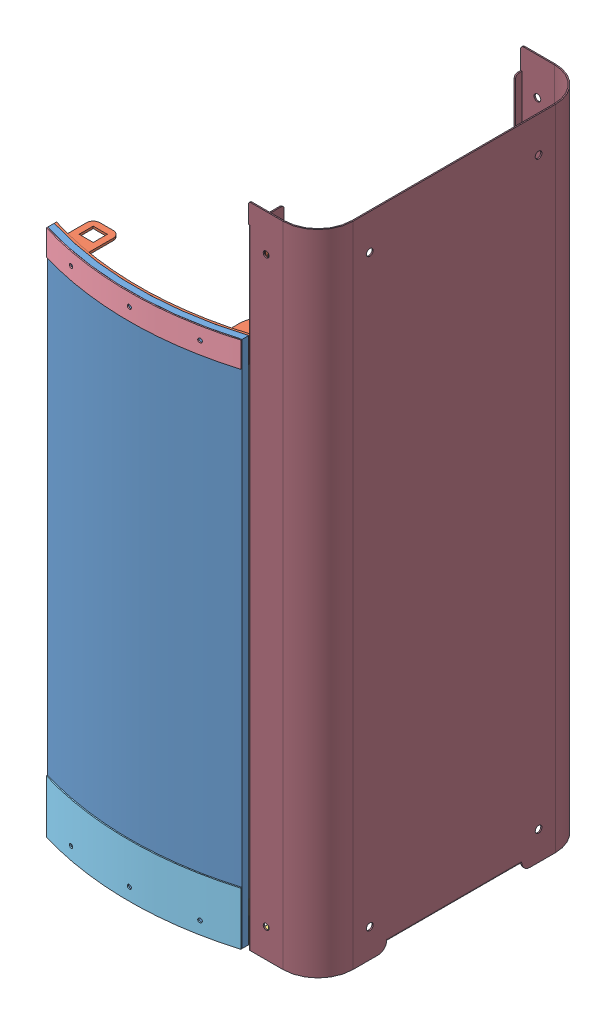
SolidWorks assembly PBS_600_DOOR, configuration Default. Lengths in mm.
Overall size (201.73 488.1 218.37).
13 component instances, 13 part files, 25 mates.
Components (placement in the parent):
- PBS_601_P_DOOR_PANEL-1: PBS_601_P_DOOR_PANEL [Default] at (0.536 -205.1011 -3.8342) size (146.34 397 15.77)
- PBS_610_S_DOOR_HINGE BRKT_T-1: PBS_610_S_DOOR_HINGE BRKT_T [Default] at (86.406 35.5639 -9.1792) x (-1 0 0) z (0 0 -1) size (165.39 19.05 41.9)
- PBS_611_S_DOOR_HINGE BRKT_B-2: PBS_611_S_DOOR_HINGE BRKT_B [Default] at (86.406 35.5639 -9.1792) x (-1 0 0) z (0 0 -1) size (165.39 19.05 41.9)
- PBS_620_S_DOOR_HINGE VALENCE_T-1: PBS_620_S_DOOR_HINGE VALENCE_T [Default] at (0.536 -205.1011 -3.8342) size (146.34 19.05 11.68)
- PBS_621_S_DOOR_HINGE VALENCE_B-1: PBS_621_S_DOOR_HINGE VALENCE_B [Default] at (0.536 -205.1011 -3.8342) size (146.34 39.88 11.68)
- PBS_605_M_DOOR_AXLE-1: PBS_605_M_DOOR_AXLE [Default] at (86.406 31.3179 -9.1792) size (8.29 473.71 9.13)
- PBS_652_X_DOOR_HINGE GEAR-1: PBS_652_X_DOOR_HINGE GEAR [Default] at (86.406 35.5639 -9.1792) size (16 6.35 16)
- PBS_650_X_DOOR_DAMPER_b-1: PBS_650_X_DOOR_DAMPER_b [Default] at (94.9554 191.421 -15.4222) x (1 0 0) z (0 1 0) size (15 24 6.6)
- PBS_631_S_DOOR_BRKT_SWITCH-1: PBS_631_S_DOOR_BRKT_SWITCH [Default] at (-74.2345 -196.269 -0.9914) size (25.53 57.15 15.88)
- PBS_654_X_DOOR_SWITCH-1: PBS_654_X_DOOR_SWITCH [Default] at (109.5595 154.0375 -21.0385) x (1 0 0) z (0 -1 0) size (28.57 6.35 44.56)
- PBS_630_S_DOOR_BRKT_DAMPER-2: PBS_630_S_DOOR_BRKT_DAMPER [Default] at (-75.646 -196.269 0.3458) size (47.5 58.8 31.61)
- PBS_640_X_DOOR_SPRING-TORQUED-1: PBS_640_X_DOOR_SPRING-TORQUED [Default] at (86.406 181.129 -9.1792) x (-0.853041 0 0.521844) z (0 -1 0) size (13.63 19.93 20.71)
- PBS_210_S_SHELL_R_b-2: PBS_210_S_SHELL_R_b [Default] at (-74.995 -196.2231 -1.3052) size (52.58 487.68 204.98)
Mates (geometry in assembly coordinates):
- Concentric1: concentric anti-aligned: cylinder of PBS_601_P_DOOR_PANEL-1 through (0.536 193.1709 -241.4064) axis (0 -1 0) radius 253.492; cylinder of PBS_610_S_DOOR_HINGE BRKT_T-1 through (0.536 174.1209 -241.4064) axis (0 1 0) radius 247.0785
- Concentric2: concentric aligned: cylinder of PBS_601_P_DOOR_PANEL-1 through (41.0204 182.3759 -33.1324) axis (0.190809 0 0.981627) radius 2.159; cylinder of PBS_610_S_DOOR_HINGE BRKT_T-1 through (41.0204 182.3759 -33.1324) axis (0.190809 0 0.981627) radius 1.524
- Concentric8: concentric anti-aligned: cylinder of PBS_601_P_DOOR_PANEL-1 through (0.536 193.1709 -241.4064) axis (0 -1 0) radius 253.492; cylinder of PBS_620_S_DOOR_HINGE VALENCE_T-1 through (0.536 174.1209 -241.4064) axis (0 1 0) radius 253.492
- Concentric9: concentric aligned: cylinder of PBS_601_P_DOOR_PANEL-1 through (41.0204 182.3759 -33.1324) axis (0.190809 0 0.981627) radius 2.159; cylinder of PBS_620_S_DOOR_HINGE VALENCE_T-1 through (41.0204 182.3759 -33.1324) axis (0.190809 0 0.981627) radius 1.524
- Concentric10: concentric aligned: cylinder of PBS_601_P_DOOR_PANEL-1 through (0.536 193.1709 -241.4064) axis (0 -1 0) radius 253.492; cylinder of PBS_621_S_DOOR_HINGE VALENCE_B-1 through (0.536 -165.2231 -241.4064) axis (0 -1 0) radius 253.492
- Concentric11: concentric aligned: cylinder of PBS_601_P_DOOR_PANEL-1 through (41.0204 -195.5761 -33.1324) axis (0.190809 0 0.981627) radius 2.159; cylinder of PBS_621_S_DOOR_HINGE VALENCE_B-1 through (41.0204 -195.5761 -33.1324) axis (0.190809 0 0.981627) radius 1.524
- Concentric12: concentric aligned: cylinder of PBS_610_S_DOOR_HINGE BRKT_T-1 through (86.406 184.3126 -9.1792) axis (0 -1 0) radius 2.4447; cylinder of PBS_605_M_DOOR_AXLE-1 through (86.406 268.1729 -9.1792) axis (0 -1 0) radius 2.3813
- Coincident1: coincident anti-aligned: plane of PBS_610_S_DOOR_HINGE BRKT_T-1 through (86.406 184.3126 -9.1792) normal (0 1 0); plane of PBS_652_X_DOOR_HINGE GEAR-1 through (86.406 184.3126 -9.1792) normal (0 -1 0)
- Concentric13: concentric aligned: cylinder of PBS_605_M_DOOR_AXLE-1 through (86.406 268.1729 -9.1792) axis (0 -1 0) radius 2.3813; cylinder of PBS_652_X_DOOR_HINGE GEAR-1 through (86.406 187.4876 -9.1792) axis (0 -1 0) radius 2.3813
- Parallel1: parallel aligned: plane of PBS_652_X_DOOR_HINGE GEAR-1 through (86.406 190.6626 -9.1792) normal (0 1 0); plane of PBS_650_X_DOOR_DAMPER_b-1 through (94.9554 193.621 -15.4222) normal (0 1 0)
- Concentric14: concentric aligned: cylinder of PBS_611_S_DOOR_HINGE BRKT_B-2 through (86.406 -192.8774 -9.1792) axis (0 -1 0) radius 2.4447; cylinder of PBS_605_M_DOOR_AXLE-1 through (86.406 268.1729 -9.1792) axis (0 -1 0) radius 2.3813
- Parallel2: parallel aligned: plane of PBS_601_P_DOOR_PANEL-1 through (-72.6351 302.8989 -5.4111) normal (-1 0 0); plane of PBS_611_S_DOOR_HINGE BRKT_B-2 through (-72.6351 302.8989 -5.4111) normal (-1 0 0)
- Concentric15: concentric anti-aligned: cylinder of PBS_605_M_DOOR_AXLE-1 through (86.406 268.1729 -9.1792) axis (0 -1 0) radius 2.3813; cylinder of PBS_630_S_DOOR_BRKT_DAMPER-2 through (86.406 188.541 -9.1792) axis (0 1 0) radius 2.4447
- Coincident2: coincident anti-aligned: plane of PBS_650_X_DOOR_DAMPER_b-1 through (94.9554 193.621 -15.4222) normal (0 1 0); plane of PBS_630_S_DOOR_BRKT_DAMPER-2 through (102.154 193.621 -25.0542) normal (0 -1 0)
- Parallel5: parallel aligned: plane of PBS_650_X_DOOR_DAMPER_b-1 through (91.4554 193.621 -8.7889) normal (-1 0 0); plane of PBS_630_S_DOOR_BRKT_DAMPER-2 through (78.405 195.272 -1.3052) normal (-1 0 0)
- Concentric16: concentric anti-aligned: cylinder of PBS_650_X_DOOR_DAMPER_b-1 through (94.9554 193.621 -5.9222) axis (0 -1 0) radius 1.05; cylinder of PBS_630_S_DOOR_BRKT_DAMPER-2 through (94.9554 188.541 -5.9222) axis (0 1 0) radius 1.6
- Coincident3: coincident anti-aligned: plane of PBS_631_S_DOOR_BRKT_SWITCH-1 through (-74.2345 193.621 -0.9914) normal (0 1 0); plane of PBS_630_S_DOOR_BRKT_DAMPER-2 through (102.154 193.621 -25.0542) normal (0 -1 0)
- Parallel6: parallel aligned: plane of PBS_631_S_DOOR_BRKT_SWITCH-1 through (121.903 191.97 -28.9125) normal (1 0 0); plane of PBS_630_S_DOOR_BRKT_DAMPER-2 through (125.903 195.272 -25.0542) normal (1 0 0)
- Distance2: distance = 4 mm aligned: plane of PBS_631_S_DOOR_BRKT_SWITCH-1 through (121.903 191.97 -28.9125) normal (1 0 0); plane of PBS_630_S_DOOR_BRKT_DAMPER-2 through (125.903 195.272 -25.0542) normal (1 0 0)
- Coincident4: coincident anti-aligned: plane of PBS_631_S_DOOR_BRKT_SWITCH-1 through (-74.2345 -196.269 -14.6885) normal (0 0 -1); plane of PBS_654_X_DOOR_SWITCH-1 through (109.5595 154.0375 -14.6885) normal (0 0 1)
- Parallel7: parallel aligned: plane of PBS_631_S_DOOR_BRKT_SWITCH-1 through (121.903 191.97 -28.9125) normal (1 0 0); plane of PBS_654_X_DOOR_SWITCH-1 through (120.672 138.1625 -14.6885) normal (1 0 0)
- Concentric18: concentric aligned: cylinder of PBS_611_S_DOOR_HINGE BRKT_B-2 through (41.0204 -195.5761 -33.1324) axis (0.190809 0 0.981627) radius 1.524; cylinder of PBS_621_S_DOOR_HINGE VALENCE_B-1 through (41.0204 -195.5761 -33.1324) axis (0.190809 0 0.981627) radius 1.524
- Parallel8: parallel anti-aligned: plane of PBS_610_S_DOOR_HINGE BRKT_T-1 through (73.707 302.8989 -5.4111) normal (1 0 0); plane of PBS_630_S_DOOR_BRKT_DAMPER-2 through (78.405 195.272 -1.3052) normal (-1 0 0)
- Distance4: distance = 4 mm aligned: plane of PBS_631_S_DOOR_BRKT_SWITCH-1 through (121.903 191.97 -28.9125) normal (0 0 -1); plane of PBS_630_S_DOOR_BRKT_DAMPER-2 through (78.405 195.272 -32.9125) normal (0 0 -1)
- Concentric20: concentric anti-aligned: cylinder of PBS_631_S_DOOR_BRKT_SWITCH-1 through (101.6286 141.439 1.6615) axis (0 0 -1) radius 1.621; cylinder of PBS_654_X_DOOR_SWITCH-1 through (101.6286 141.439 -31.0385) axis (0 0 1) radius 1.5875
